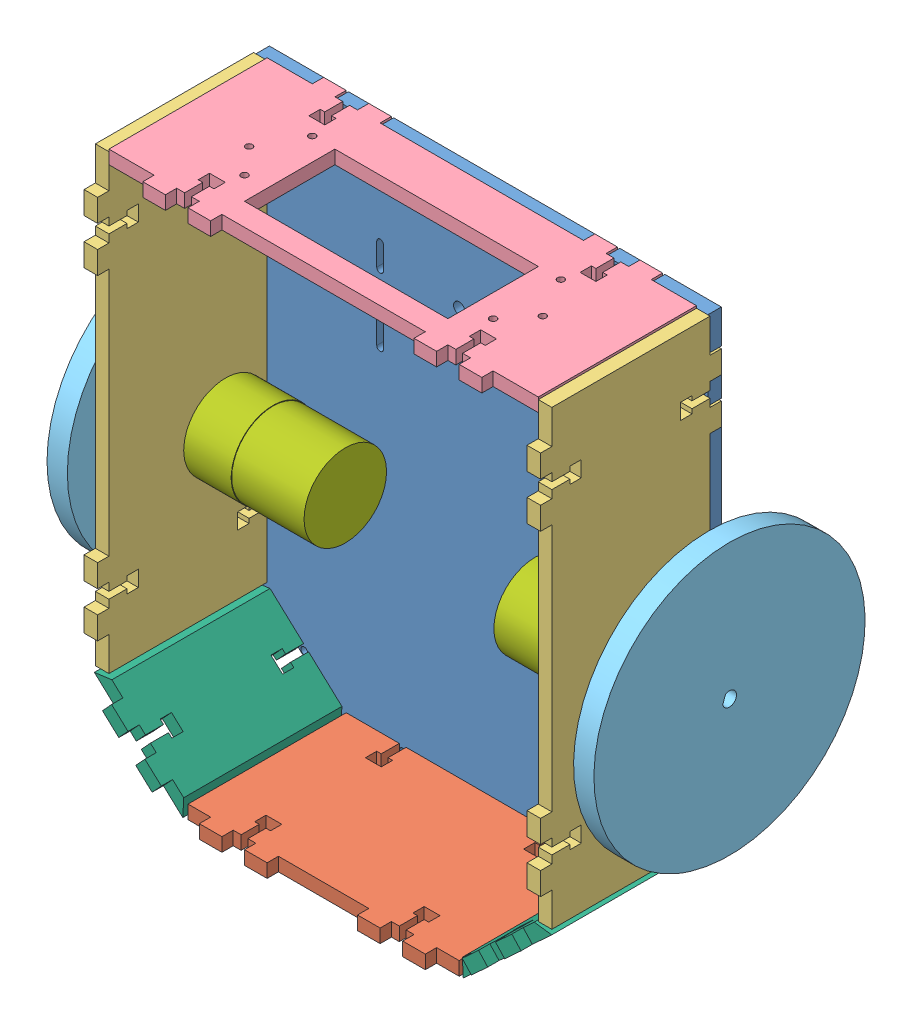
SolidWorks assembly roboComRoda, configuration Valor predeterminado. Lengths in mm.
Overall size (242 239.83 153.89).
11 component instances, 7 part files, 30 mates.
Components (placement in the parent):
- chassi-1: chassi [Valor predeterminado] at (112.0239 130.1265 -3) size (200 237.62 6)
- frente-1: frente [Valor predeterminado] at (-47.9761 -108.3735 3) x (0 0 -1) z (0 1 0) size (80 120 6)
- lateral-1: lateral [Valor predeterminado] at (107.0239 -69.8735 3) x (0 0 1) z (1 0 0) size (80 200 6)
- lateral-2: lateral [Valor predeterminado] at (-88.9761 -69.8735 3) x (0 0 1) z (1 0 0) size (80 200 6)
- traseira-1: traseira [Valor predeterminado] at (-82.9761 131.1265 73) x (1 0 0) z (0 -1 0) size (190 80 6)
- roda-3: roda [Valor predeterminado] at (133.0239 -0.8735 14.4) x (0 -0.939303 0.343089) z (-1 0 0) size (120 120 16)
- roda-4: roda [Valor predeterminado] at (-108.9761 -0.8735 14.4) x (0 0 -1) z (1 0 0) size (120 120 16)
- ladoNovo-4: ladoNovo [Valor predeterminado] at (109.4495 -67.1244 38) x (0 0 -1) z (0.677799 -0.735247 0) size (80 53.24 6)
- ladoNovo-5: ladoNovo [Valor predeterminado] at (-85.9061 -67.6986 38) x (0 0 1) z (-0.677799 -0.735247 0) size (80 53.24 6)
- motor-1: motor [Valor predeterminado] at (107.0239 -0.8735 14.4) x (0 0 1) z (-1 0 0) size (37 37 74)
- motor-2: motor [Valor predeterminado] at (-82.9761 -0.8735 14.4) x (0 0 1) z (1 0 0) size (37 37 74)
Mates (geometry in assembly coordinates):
- Coincidente1: coincident anti-aligned: plane of chassi-1 through (112.0239 130.1265 3) normal (0 0 1); plane of traseira-1 through (-32.9761 125.1265 3) normal (0 0 -1)
- Coincidente2: coincident anti-aligned: plane of chassi-1 through (87.0239 125.1265 3) normal (0 1 0); plane of traseira-1 through (-82.9761 125.1265 73) normal (0 -1 0)
- Largura1: width anti-aligned: plane of chassi-1 through (77.0239 125.1265 3) normal (1 0 0); plane of chassi-1 through (67.0239 130.1265 3) normal (-1 0 0); plane of traseira-1 through (77.0239 125.1265 3) normal (-1 0 0); plane of traseira-1 through (67.0239 125.1265 -2) normal (1 0 0)
- Coincidente3: coincident anti-aligned: plane of chassi-1 through (112.0239 130.1265 3) normal (0 0 1); plane of lateral-2 through (-82.9761 -24.8735 3) normal (0 0 -1)
- Coincidente5: coincident anti-aligned: plane of chassi-1 through (-82.9761 -24.8735 3) normal (-1 0 0); plane of lateral-2 through (-82.9761 -69.8735 3) normal (1 0 0)
- Largura3: width anti-aligned: plane of lateral-2 through (-82.9761 -34.8735 3) normal (0 -1 0); plane of lateral-2 through (-82.9761 -44.8735 -2) normal (0 1 0); plane of chassi-1 through (-82.9761 -34.8735 3) normal (0 1 0); plane of chassi-1 through (-87.9761 -44.8735 3) normal (0 -1 0)
- Coincidente6: coincident anti-aligned: plane of chassi-1 through (107.0239 -54.8735 3) normal (1 0 0); plane of lateral-1 through (107.0239 -69.8735 3) normal (-1 0 0)
- Coincidente7: coincident anti-aligned: plane of chassi-1 through (112.0239 130.1265 3) normal (0 0 1); plane of lateral-1 through (113.0239 -24.8735 3) normal (0 0 -1)
- Largura4: width anti-aligned: plane of lateral-1 through (113.0239 -34.8735 3) normal (0 -1 0); plane of lateral-1 through (113.0239 -44.8735 -2) normal (0 1 0); plane of chassi-1 through (112.0239 -34.8735 3) normal (0 1 0); plane of chassi-1 through (107.0239 -44.8735 3) normal (0 -1 0)
- Coincidente8: coincident anti-aligned: plane of chassi-1 through (112.0239 130.1265 3) normal (0 0 1); plane of frente-1 through (32.0239 -102.3735 3) normal (0 0 -1)
- Coincidente9: coincident anti-aligned: plane of chassi-1 through (52.0239 -102.3735 3) normal (0 -1 0); plane of frente-1 through (-47.9761 -102.3735 3) normal (0 1 0)
- Largura6: width anti-aligned: plane of frente-1 through (52.0239 -102.3735 -2) normal (-1 0 0); plane of frente-1 through (42.0239 -102.3735 3) normal (1 0 0); plane of chassi-1 through (52.0239 -107.3735 3) normal (1 0 0); plane of chassi-1 through (42.0239 -102.3735 3) normal (-1 0 0)
- Coincidente29: coincident anti-aligned: plane of chassi-1 through (78.264 -95.8733 3) normal (0.677799 -0.735247 0); plane of ladoNovo-4 through (109.4495 -67.1244 38) normal (-0.677799 0.735247 0)
- Paralelo5: parallel aligned: line of frente-1 through (72.0239 -108.3735 73) axis (0 0 -1); line of ladoNovo-4 through (73.8203 -108.1303 73) axis (0 0 -1)
- Distância1: distance = 0.05 mm anti-aligned: plane of chassi-1 through (85.6164 -89.0953 3) normal (-0.735247 -0.677799 0); plane of ladoNovo-4 through (89.6465 -93.5406 3) normal (0.735247 0.677799 0)
- Coincidente31: coincident anti-aligned: plane of chassi-1 through (112.0239 130.1265 3) normal (0 0 1); plane of ladoNovo-4 through (113.5163 -71.5359 3) normal (0 0 -1)
- Coincidente33: coincident anti-aligned: plane of chassi-1 through (112.0239 130.1265 3) normal (0 0 1); plane of ladoNovo-5 through (-89.9729 -72.11 3) normal (0 0 -1)
- Distância2: distance = 0.05 mm anti-aligned: plane of ladoNovo-5 through (-66.1031 -94.1148 3) normal (-0.735247 0.677799 0); plane of chassi-1 through (-64.4776 -92.2777 3) normal (0.735247 -0.677799 0)
- Coincidente34: coincident: plane of chassi-1 through (-62.0731 -89.6694 3) normal (-0.677799 -0.735247 0); plane of ladoNovo-5 through (-85.9061 -67.6986 38) normal (0.677799 0.735247 0)
- Coincidente35: coincident anti-aligned: plane of chassi-1 through (-62.0731 -89.6694 3) normal (-0.677799 -0.735247 0); plane of ladoNovo-5 through (-85.9061 -67.6986 38) normal (0.677799 0.735247 0)
- Concêntrico3: concentric anti-aligned: cylinder of lateral-2 through (-82.9761 -0.8735 14.4) axis (-1 0 0) radius 6; cylinder of motor-2 through (-88.9761 -0.8735 14.4) axis (1 0 0) radius 6
- Concêntrico4: concentric aligned: circle of lateral-2; circle of motor-2
- Coincidente37: coincident anti-aligned: plane of lateral-2 through (-82.9761 -69.8735 3) normal (1 0 0); plane of motor-2 through (-82.9761 -0.8935 21.403) normal (-1 0 0)
- Concêntrico5: concentric aligned: cylinder of lateral-1 through (113.0239 -0.8735 14.4) axis (-1 0 0) radius 6; cylinder of motor-1 through (113.0239 -0.8735 14.4) axis (-1 0 0) radius 6
- Concêntrico6: concentric aligned: cylinder of lateral-1 through (113.0239 -0.8735 38.353) axis (-1 0 0) radius 1.25; circle of motor-1
- Coincidente39: coincident anti-aligned: plane of lateral-1 through (107.0239 -69.8735 3) normal (-1 0 0); plane of motor-1 through (107.0239 -0.8535 21.403) normal (1 0 0)
- Concêntrico7: concentric: cylinder of roda-3 through (124.0239 -0.8735 14.4) axis (1 0 0) radius 3.125; cylinder of motor-1 through (128.0239 -0.8735 14.4) axis (-1 0 0) radius 2
- Distância3: distance = 5 mm aligned: plane of roda-3 through (133.0239 -0.8735 14.4) normal (1 0 0); plane of motor-1 through (128.0239 -0.8735 14.4) normal (1 0 0)
- Concêntrico8: concentric: cylinder of roda-4 through (-99.9761 -0.8735 14.4) axis (-1 0 0) radius 3.125; cylinder of motor-2 through (-103.9761 -0.8735 14.4) axis (1 0 0) radius 2
- Distância4: distance = 5 mm aligned: plane of motor-2 through (-103.9761 -0.8735 14.4) normal (-1 0 0); plane of roda-4 through (-108.9761 -0.8735 14.4) normal (-1 0 0)
